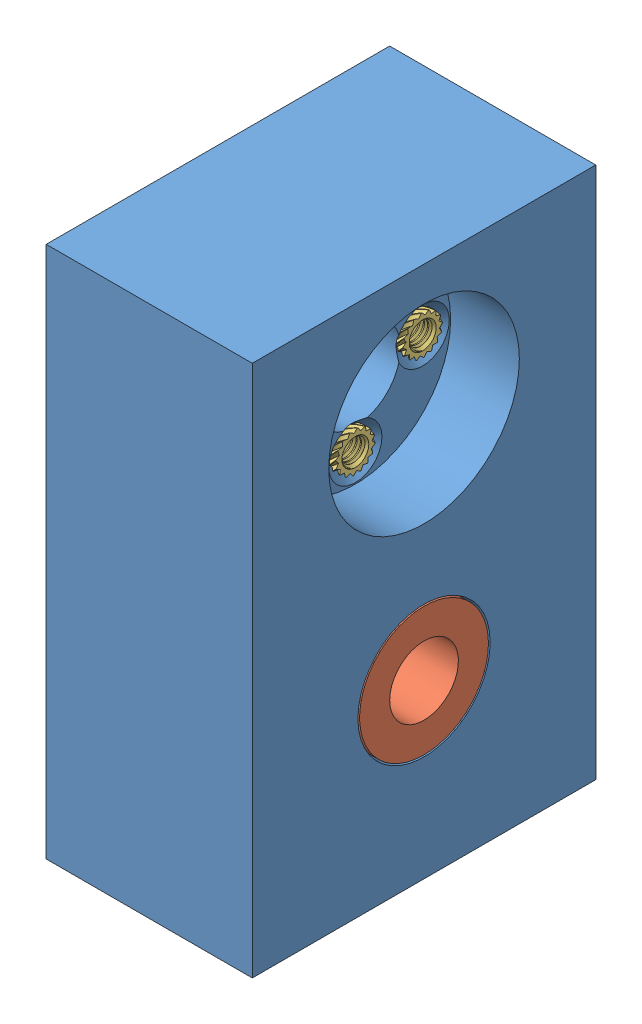
SolidWorks assembly Assem1, configuration Default. Lengths in mm.
Overall size (24 62 40).
12 component instances, 4 part files, 22 mates.
Components (placement in the parent):
- Holder-1: Holder [Default] at (-45.2805 -34.7401 30.5112) size (24 62 40)
- 8mm Linear Bearing-1: 8mm Linear Bearing [Default] at (-57.2805 -14.7401 30.5112) x (0 -0.999975 0.007121) z (0 0.007121 0.999975) size (32 24 32)
- 8mm Lead Screw Nut-1: 8mm Lead Screw Nut [Default] at (-41.2805 12.1599 30.5112) x (0 -1 0) z (0 0 -1) (suppressed, hidden)
- M3_Standard.step-1: M3_Standard.step [Default] at (-46.5805 -2.7901 30.5112) x (0 0.123123 0.992391) z (-1 0 0) size (4.67 4.67 5.76)
- M3_Standard.step-3: M3_Standard.step [Default] at (-46.5805 -14.7401 42.4612) x (0 -0.035781 0.99936) z (-1 0 0) size (4.67 4.67 5.76)
- M3_Standard.step-5: M3_Standard.step [Default] at (-46.5805 -26.6901 30.5112) x (0 -0.162741 0.986669) z (-1 0 0) size (4.67 4.67 5.76)
- M3_Standard.step-7: M3_Standard.step [Default] at (-45.5805 -0.5454 35.1379) x (0 -0.254002 0.967204) z (-1 0 0) size (4.67 4.67 5.76)
- M3_Standard.step-9: M3_Standard.step [Default] at (-46.5805 -14.7401 18.5612) x (0 -0.306278 0.951942) z (-1 0 0) size (4.67 4.67 5.76)
- M3_Standard.step-11: M3_Standard.step [Default] at (-46.9805 20.0051 30.5112) x (0 0.732214 -0.681074) z (1 0 0) size (4.67 4.67 5.76)
- M3_Standard.step-14: M3_Standard.step [Default] at (-46.9805 12.1599 22.666) x (0 0.602823 -0.797875) z (1 0 0) size (4.67 4.67 5.76)
- M3_Standard.step-16: M3_Standard.step [Default] at (-46.9805 4.3146 30.5112) x (0 0.455115 -0.890433) z (1 0 0) size (4.67 4.67 5.76)
- M3_Standard.step-18: M3_Standard.step [Default] at (-46.9805 12.1599 38.3565) x (0 0.293579 -0.955935) z (1 0 0) size (4.67 4.67 5.76)
Mates (geometry in assembly coordinates):
- Concentric5: concentric anti-aligned: cylinder of Holder-1 through (-27.2805 -14.7401 30.5112) axis (-1 0 0) radius 7.7; cylinder of 8mm Linear Bearing-1 through (-83.2805 -14.7401 30.5112) axis (1 0 0) radius 4
- Coincident5: coincident anti-aligned: plane of Holder-1 through (-52.2805 -14.7401 30.5112) normal (-1 0 0); plane of 8mm Linear Bearing-1 through (-52.2805 -14.7401 30.5112) normal (1 0 0)
- Concentric8: concentric anti-aligned: cylinder of Holder-1 through (-69.1599 12.1599 30.5112) axis (1 0 0) radius 4.2; cylinder of 8mm Lead Screw Nut-1 through (-19.0116 12.1599 30.5112) axis (-1 0 0) radius 4
- Parallel1: parallel anti-aligned: plane of 8mm Lead Screw Nut-1 through (-41.2805 12.1599 30.5112) normal (0 -1 0)
- Coincident8: coincident anti-aligned: plane of Holder-1 through (-41.2805 12.1599 30.5112) normal (1 0 0); plane of 8mm Lead Screw Nut-1 through (-41.2805 12.1599 30.5112) normal (-1 0 0)
- Coincident10: coincident aligned: plane of Holder-1 through (-52.2805 -14.7401 30.5112) normal (-1 0 0); plane of M3_Standard.step-1 through (-52.2805 -2.6054 31.9998) normal (-1 0 0)
- Concentric10: concentric aligned: circle of Holder-1; circle of M3_Standard.step-1
- Coincident12: coincident aligned: plane of Holder-1 through (-52.2805 -14.7401 30.5112) normal (-1 0 0); plane of M3_Standard.step-3 through (-52.2805 -14.7938 43.9603) normal (-1 0 0)
- Concentric12: concentric aligned: circle of Holder-1; circle of M3_Standard.step-3
- Coincident13: coincident aligned: plane of Holder-1 through (-52.2805 -14.7401 30.5112) normal (-1 0 0); plane of M3_Standard.step-5 through (-52.2805 -26.9342 31.9912) normal (-1 0 0)
- Concentric13: concentric aligned: circle of Holder-1; circle of M3_Standard.step-5
- Coincident14: coincident aligned: circle of Holder-1; plane of M3_Standard.step-7 through (-51.2805 -0.9264 36.5887) normal (-1 0 0)
- Coincident15: coincident aligned: plane of Holder-1 through (-52.2805 -14.7401 30.5112) normal (-1 0 0); plane of M3_Standard.step-9 through (-52.2805 -15.1995 19.9891) normal (-1 0 0)
- Concentric14: concentric aligned: circle of Holder-1; circle of M3_Standard.step-9
- Coincident16: coincident aligned: plane of Holder-1 through (-41.2805 12.1599 30.5112) normal (1 0 0); plane of M3_Standard.step-11 through (-41.2805 21.1034 29.4896) normal (1 0 0)
- Concentric15: concentric aligned: circle of Holder-1; circle of M3_Standard.step-11
- Coincident18: coincident aligned: plane of Holder-1 through (-41.2805 12.1599 30.5112) normal (1 0 0); plane of M3_Standard.step-14 through (-41.2805 13.0641 21.4692) normal (1 0 0)
- Concentric17: concentric aligned: circle of Holder-1; circle of M3_Standard.step-14
- Coincident19: coincident aligned: plane of Holder-1 through (-41.2805 12.1599 30.5112) normal (1 0 0); plane of M3_Standard.step-16 through (-41.2805 4.9973 29.1756) normal (1 0 0)
- Concentric18: concentric aligned: circle of Holder-1; circle of M3_Standard.step-16
- Coincident20: coincident aligned: plane of Holder-1 through (-41.2805 12.1599 30.5112) normal (1 0 0); plane of M3_Standard.step-18 through (-41.2805 12.6002 36.9226) normal (1 0 0)
- Concentric19: concentric aligned: circle of Holder-1; circle of M3_Standard.step-18
